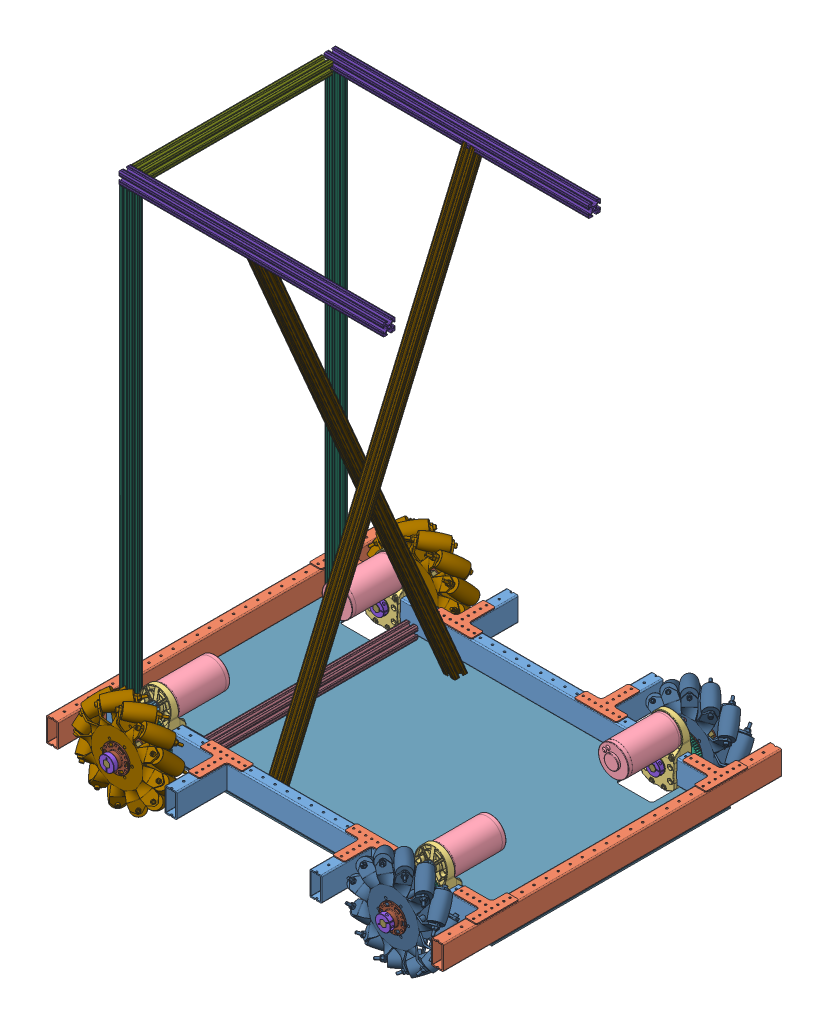
SolidWorks assembly 2018-202-Chassis, configuration Default. Lengths in mm.
Overall size (847.68 1105.96 717.55).
78 component instances, 20 part files, 152 mates.
Components (placement in the parent):
- 2018-200-D002-1: 2018-200-D002 [Default] at (0 101.6 241.3) x (0 0 -1) z (1 0 0) size (25.4 50.8 784.22)
- 2018-200-D002-2: 2018-200-D002 [Default] at (0 101.6 -241.3) x (0 0 -1) z (1 0 0) size (25.4 50.8 784.22)
- 2018-200-D001-2: 2018-200-D001 [Default] at (-404.8125 101.6 0) size (25.4 50.8 711.2)
- 2018-201A-1: 2018-201A [Default] at (-290.5125 96.52 234.85) x (-1 0 0) z (0 0 -1) size (91.39 133.93 154.93)
  - 2018-200-D003-1: 2018-200-D003 [Default] at origin size (69.6 129.7 39.75)
  - 2018-201-D001-1: 2018-201-D001 [Default] at (35.56 -50.8 10.8) x (-1 0 0) z (0 0 -1) size (64.01 64.01 154.93)
  - 2018-201-D002-1: 2018-201-D002 [Default] at (0 58.4962 -28.318) x (0 1 0) z (0 0 1) size (20.01 20.32 19.05)
  - 2018-201-D003-1: 2018-201-D003 [Default] at (0 5.08 -33.0805) size (91.39 91.44 12.65)
  - 2018-201-D007-1: 2018-201-D007 [Default] at (0 5.08 6.35) x (0.5 0.866025 0) z (0.866025 -0.5 0) size (31.12 7.94 31.12)
  - 2018-201-D007-2: 2018-201-D007 [Default] at (0 5.08 -19.05) x (-0.5 -0.866025 0) z (0.866025 -0.5 0) size (31.12 7.94 31.12)
  - 2018-200-D006-1: 2018-200-D006 [Default] at (0.0058 5.07 23.8125) x (1 0 0) z (0 1 0) size (31.47 9.53 31.5)
- 2018-201A-2: 2018-201A [Default] at (290.5125 96.52 234.85) x (-1 0 0) z (0 0 -1) size (91.39 133.93 154.93)
  - 2018-200-D003-1: 2018-200-D003 [Default] at origin size (69.6 129.7 39.75)
  - 2018-201-D001-1: 2018-201-D001 [Default] at (35.56 -50.8 10.8) x (-1 0 0) z (0 0 -1) size (64.01 64.01 154.93)
  - 2018-201-D002-1: 2018-201-D002 [Default] at (0 58.4962 -28.318) x (0 1 0) z (0 0 1) size (20.01 20.32 19.05)
  - 2018-201-D003-1: 2018-201-D003 [Default] at (0 5.08 -33.0805) size (91.39 91.44 12.65)
  - 2018-201-D007-1: 2018-201-D007 [Default] at (0 5.08 6.35) x (0.5 0.866025 0) z (0.866025 -0.5 0) size (31.12 7.94 31.12)
  - 2018-201-D007-2: 2018-201-D007 [Default] at (0 5.08 -19.05) x (-0.5 -0.866025 0) z (0.866025 -0.5 0) size (31.12 7.94 31.12)
  - 2018-200-D006-1: 2018-200-D006 [Default] at (0.0058 5.07 23.8125) x (1 0 0) z (0 1 0) size (31.47 9.53 31.5)
- 2018-201A-3: 2018-201A [Default] at (-290.5125 96.52 -235.05) size (91.39 133.93 154.93)
  - 2018-200-D003-1: 2018-200-D003 [Default] at origin size (69.6 129.7 39.75)
  - 2018-201-D001-1: 2018-201-D001 [Default] at (35.56 -50.8 10.8) x (-1 0 0) z (0 0 -1) size (64.01 64.01 154.93)
  - 2018-201-D002-1: 2018-201-D002 [Default] at (0 58.4962 -28.318) x (0 1 0) z (0 0 1) size (20.01 20.32 19.05)
  - 2018-201-D003-1: 2018-201-D003 [Default] at (0 5.08 -33.0805) size (91.39 91.44 12.65)
  - 2018-201-D007-1: 2018-201-D007 [Default] at (0 5.08 6.35) x (0.5 0.866025 0) z (0.866025 -0.5 0) size (31.12 7.94 31.12)
  - 2018-201-D007-2: 2018-201-D007 [Default] at (0 5.08 -19.05) x (-0.5 -0.866025 0) z (0.866025 -0.5 0) size (31.12 7.94 31.12)
  - 2018-200-D006-1: 2018-200-D006 [Default] at (0.0058 5.07 23.8125) x (1 0 0) z (0 1 0) size (31.47 9.53 31.5)
- 2018-201A-4: 2018-201A [Default] at (290.5125 96.52 -235.05) size (91.39 133.93 154.93)
  - 2018-200-D003-1: 2018-200-D003 [Default] at origin size (69.6 129.7 39.75)
  - 2018-201-D001-1: 2018-201-D001 [Default] at (35.56 -50.8 10.8) x (-1 0 0) z (0 0 -1) size (64.01 64.01 154.93)
  - 2018-201-D002-1: 2018-201-D002 [Default] at (0 58.4962 -28.318) x (0 1 0) z (0 0 1) size (20.01 20.32 19.05)
  - 2018-201-D003-1: 2018-201-D003 [Default] at (0 5.08 -33.0805) size (91.39 91.44 12.65)
  - 2018-201-D007-1: 2018-201-D007 [Default] at (0 5.08 6.35) x (0.5 0.866025 0) z (0.866025 -0.5 0) size (31.12 7.94 31.12)
  - 2018-201-D007-2: 2018-201-D007 [Default] at (0 5.08 -19.05) x (-0.5 -0.866025 0) z (0.866025 -0.5 0) size (31.12 7.94 31.12)
  - 2018-200-D006-1: 2018-200-D006 [Default] at (0.0058 5.07 23.8125) x (1 0 0) z (0 1 0) size (31.47 9.53 31.5)
- 2018-200-D001-3: 2018-200-D001 [Default] at (404.8125 101.6 0) size (25.4 50.8 711.2)
- 2018-200-D004-Left-1: 2018-200-D004-Left [Default] at (-277.7318 118.2849 307.4097) x (-1 0 0) z (0 0 1) size (208.7 208.7 65.41)
- 2018-200-D004-Left-2: 2018-200-D004-Left [Default] at (-269.698 104.3993 -307.6097) x (-0.5 -0.866025 0) z (0 0 -1) size (208.7 208.7 65.41)
- 2018-200-D004-Right-1: 2018-200-D004-Right [Default] at (259.1745 95.1764 -310.8452) size (213.35 213.35 65.46)
- 2018-200-D004-Right-2: 2018-200-D004-Right [Default] at (319.1455 87.387 310.6452) x (-0.965926 0.258819 0) z (0 0 -1) size (213.35 213.35 65.46)
- 2018-200-D005-1: 2018-200-D005 [Default] at (-290.5379 101.6733 -346.8451) x (0 0 1) z (-0.5 -0.866025 0) size (12.7 55.88 55.88)
- 2018-200-D005-2: 2018-200-D005 [Default] at (-290.5379 101.6733 -274.4551) x (0 0 -1) z (0.5 0.866025 0) size (12.7 55.88 55.88)
- 2018-200-D005-3: 2018-200-D005 [Default] at (-290.5125 101.6 346.6451) x (0 0 -1) z (-0.5 -0.866025 0) size (12.7 55.88 55.88)
- 2018-200-D005-5: 2018-200-D005 [Default] at (-290.5125 101.6 274.2551) x (0 0 1) z (1 0 0) size (12.7 55.88 55.88)
- 2018-200-D006-1: 2018-200-D006 [Default] at (-290.5252 101.6073 356.1701) x (0 -1 0) z (1 0 0) size (31.47 9.53 31.5)
- 2018-200-D006-2: 2018-200-D006 [Default] at (290.5506 101.6953 356.1701) x (0.866025 0.5 0) z (-0.5 0.866025 0) size (31.47 9.53 31.5)
- 2018-200-D006-3: 2018-200-D006 [Default] at (-290.5252 101.6513 -346.8451) x (0 1 0) z (-1 0 0) size (31.47 9.53 31.5)
- 2018-200-D006-4: 2018-200-D006 [Default] at (290.5087 101.5858 -346.8451) x (-0.707107 0.707107 0) z (-0.707107 -0.707107 0) size (31.47 9.53 31.5)
- 2018-200-D005-6: 2018-200-D005 [Default] at (290.5379 101.7027 346.6451) x (0 0 -1) z (1 0 0) size (12.7 55.88 55.88)
- 2018-200-D005-7: 2018-200-D005 [Default] at (290.5125 101.6 -274.4551) x (0 0 -1) z (0.707107 0.707107 0) size (12.7 55.88 55.88)
- 2018-200-D005-9: 2018-200-D005 [Default] at (290.5125 101.6 -346.8451) x (0 0 1) z (-0.965926 0.258819 0) size (12.7 55.88 55.88)
- 2018-200-D005-10: 2018-200-D005 [Default] at (290.5379 101.7027 274.2551) x (0 0 1) z (0.5 -0.866025 0) size (12.7 55.88 55.88)
- 2018-200-D007-1: 2018-200-D007 [Default] at (290.5633 101.688 438.7201) x (0 -1 0) z (0 0 1) size (14.48 12.67 146.05)
- 2018-200-D007-2: 2018-200-D007 [Default] at (-290.5252 101.5927 438.7201) x (-0.866025 0.5 0) z (0 0 1) size (14.48 12.67 146.05)
- 2018-200-D007-3: 2018-200-D007 [Default] at (-290.5125 101.6587 -127.7701) x (-0.866025 -0.5 0) z (0 0 1) size (14.48 12.67 146.05)
- 2018-200-D007-4: 2018-200-D007 [Default] at (290.5229 101.5896 -127.7701) x (-0.258819 -0.965926 0) z (0 0 1) size (14.48 12.67 146.05)
- 2018-200-D009-1: 2018-200-D009 [Default] at (-227.0125 88.9 228.6) size (25.4 25.4 450.85)
- 2018-200-D008-1: 2018-200-D008 [Default] at (0 74.6125 3.175) size (835.02 3.17 501.65)
- 2018-200-D010-1: 2018-200-D010 [Default] at (-379.4125 590.55 215.9) x (1 0 0) z (0 -1 0) size (25.4 25.4 965.2)
- 2018-200-D010-2: 2018-200-D010 [Default] at (-379.4125 527.05 -215.9) x (1 0 0) z (0 1 0) size (25.4 25.4 965.2)
- 2018-200-D011-1: 2018-200-D011 [Default] at (-379.4125 1054.1 254) size (25.4 25.4 400.05)
- 2018-200-D012-1: 2018-200-D012 [Default] at (-287.3375 1054.1 215.9) x (0 0 1) z (-1 0 0) size (25.4 25.4 555.62) (hidden)
- 2018-200-D012-2: 2018-200-D012 [Default] at (-287.3375 1054.1 -215.9) x (0 0 1) z (-1 0 0) size (25.4 25.4 555.62)
- 2018-200-D013-1: 2018-200-D013 [Default] at (-114.3 965.3313 180.0515) x (1 0 0) z (0 0.91886 0.394583) size (25.4 25.4 1069)
- 2018-200-D012-3: 2018-200-D012 [Default] at (-287.3375 1054.1 215.9) x (0 0 1) z (-1 0 0) size (25.4 25.4 555.62)
- 2018-200-D013-2: 2018-200-D013 [Default] at (-88.9 965.3313 -180.0515) x (-1 0 0) z (0 0.91886 -0.394583) size (25.4 25.4 1069)
- 2018-200-D014-1: 2018-200-D014 [Default] at (-152.4 101.6 306.3875) size (25.4 50.8 104.77)
- 2018-200-D014-2: 2018-200-D014 [Default] at (152.4 101.6 306.3875) size (25.4 50.8 104.77)
- 2018-200-D014-3: 2018-200-D014 [Default] at (152.4 101.6 -306.3875) size (25.4 50.8 104.77)
- 2018-200-D014-4: 2018-200-D014 [Default] at (-152.4 101.6 -306.3875) size (25.4 50.8 104.77)
- 2018-200-D015-1: 2018-200-D015 [Default] at (-152.4 129.286 -254) x (1 0 0) z (0 -1 0) size (88.9 82.55 2.29)
- 2018-200-D015-2: 2018-200-D015 [Default] at (392.1125 127 241.3) x (0 0 1) z (0 1 0) size (88.9 82.55 2.29)
- 2018-200-D015-3: 2018-200-D015 [Default] at (392.1125 129.286 -241.3) x (0 0 -1) z (0 -1 0) size (88.9 82.55 2.29)
- 2018-200-D015-4: 2018-200-D015 [Default] at (152.4 129.286 -254) x (1 0 0) z (0 -1 0) size (88.9 82.55 2.29)
- 2018-200-D015-5: 2018-200-D015 [Default] at (-392.1125 129.286 241.3) x (0 0 1) z (0 -1 0) size (88.9 82.55 2.29) (hidden)
- 2018-200-D015-6: 2018-200-D015 [Default] at (152.4 127 254) x (1 0 0) z (0 1 0) size (88.9 82.55 2.29)
- 2018-200-D015-7: 2018-200-D015 [Default] at (-392.1125 129.286 -241.3) x (0 0 1) z (0 -1 0) size (88.9 82.55 2.29)
- 2018-200-D015-8: 2018-200-D015 [Default] at (-152.4 127 254) x (1 0 0) z (0 1 0) size (88.9 82.55 2.29)
Mates (geometry in assembly coordinates):
- Coincident5: coincident aligned: plane of 2018-200-D002-1 through (-392.1125 127 254) normal (0 1 0); plane of 2018-200-D001-2 through (-417.5125 127 -355.6) normal (0 1 0)
- Coincident9: coincident aligned: plane of 2018-200-D002-2 through (0 101.6 -228.6) normal (1 0 0); plane of assembly through (0 0 0) normal (1 0 0)
- Coincident23: coincident anti-aligned: plane of 2018-200-D002-2 through (0 101.6 -241.3) normal (0 0 -1); plane of 2018-201A-4/2018-200-D003-1 through (255.6275 71.12 -241.3) normal (0 0 1)
- Parallel3: parallel anti-aligned: plane of 2018-200-D002-2 through (392.1125 76.2 -215.9) normal (0 -1 0); plane of 2018-201A-4/2018-200-D003-1 through (256.7625 71.12 -216.1) normal (0 1 0)
- Coincident24: coincident anti-aligned: plane of 2018-200-D002-2 through (0 101.6 -241.3) normal (0 0 -1); plane of 2018-201A-3/2018-200-D003-1 through (-325.3975 71.12 -241.3) normal (0 0 1)
- Parallel4: parallel anti-aligned: plane of 2018-200-D002-2 through (392.1125 76.2 -215.9) normal (0 -1 0); plane of 2018-201A-3/2018-200-D003-1 through (-325.3975 71.12 -222.35) normal (0 1 0)
- Coincident26: coincident anti-aligned: plane of 2018-200-D002-1 through (0 101.6 228.6) normal (0 0 -1); plane of 2018-201A-2/2018-200-D003-1 through (324.2625 71.12 228.6) normal (0 0 1)
- Parallel5: parallel anti-aligned: plane of 2018-200-D002-1 through (392.1125 76.2 254) normal (0 -1 0); plane of 2018-201A-2/2018-200-D003-1 through (325.3975 71.12 234.85) normal (0 1 0)
- Concentric24: concentric aligned: cylinder of 2018-200-D002-1 through (-290.5125 101.6 254) axis (0 0 -1) radius 14.3002; cylinder of 2018-201A-1/2018-200-D003-1 through (-290.5125 101.6 237.85) axis (0 0 -1) radius 14.3002
- Coincident27: coincident anti-aligned: plane of 2018-200-D002-1 through (0 101.6 228.6) normal (0 0 -1); plane of 2018-201A-1/2018-200-D003-1 through (-256.7625 71.12 228.6) normal (0 0 1)
- Parallel6: parallel anti-aligned: plane of 2018-200-D002-1 through (392.1125 76.2 254) normal (0 -1 0); plane of 2018-201A-1/2018-200-D003-1 through (-255.6275 71.12 234.85) normal (0 1 0)
- Concentric25: concentric anti-aligned: cylinder of 2018-200-D002-2 through (-290.5125 101.6 -215.9) axis (0 0 -1) radius 14.3002; cylinder of 2018-201A-3/2018-200-D003-1 through (-290.5125 101.6 -225.35) axis (0 0 1) radius 14.3002
- Coincident31: coincident aligned: plane of 2018-200-D001-2 through (-404.8125 101.6 0) normal (0 0 1); plane of assembly through (0 0 0) normal (0 0 1)
- Coincident32: coincident aligned: plane of 2018-200-D002-1 through (-392.1125 127 254) normal (0 1 0); plane of 2018-200-D002-2 through (-392.1125 127 -215.9) normal (0 1 0)
- Coincident34: coincident anti-aligned: plane of 2018-200-D002-1 through (-392.1125 76.2 254) normal (-1 0 0); plane of 2018-200-D001-2 through (-392.1125 101.6 0) normal (1 0 0)
- Coincident35: coincident anti-aligned: plane of 2018-200-D002-2 through (-392.1125 76.2 -215.9) normal (-1 0 0); plane of 2018-200-D001-2 through (-392.1125 101.6 0) normal (1 0 0)
- Distance5: distance = 101.6 mm aligned: plane of 2018-200-D002-1 through (0 101.6 254) normal (0 0 1); plane of 2018-200-D001-2 through (-417.5125 127 355.6) normal (0 0 1)
- Distance6: distance = 101.6 mm aligned: plane of 2018-200-D002-1; plane of assembly through (0 0 0) normal (0 1 0)
- Distance9: distance = 101.6 mm aligned: plane of 2018-200-D002-2 through (0 101.6 -254) normal (0 0 -1); plane of 2018-200-D001-2 through (-417.5125 76.2 -355.6) normal (0 0 -1)
- Coincident40: coincident anti-aligned: plane of 2018-200-D002-1 through (392.1125 127 254) normal (1 0 0); plane of 2018-200-D001-3 through (392.1125 101.6 0) normal (-1 0 0)
- Coincident41: coincident aligned: plane of 2018-200-D001-2 through (-417.5125 127 -355.6) normal (0 1 0); plane of 2018-200-D001-3 through (392.1125 127 -355.6) normal (0 1 0)
- Coincident42: coincident aligned: plane of 2018-200-D001-2 through (-417.5125 127 355.6) normal (0 0 1); plane of 2018-200-D001-3 through (392.1125 127 355.6) normal (0 0 1)
- Concentric27: concentric anti-aligned: cylinder of 2018-200-D002-1 through (-290.5125 101.6 254) axis (0 0 -1) radius 14.3002; cylinder of 2018-200-D004-Left-1 through (-290.5125 101.6 342.4604) axis (0 0 1) radius 14.2875
- Concentric28: concentric aligned: cylinder of 2018-200-D002-2 through (290.5125 101.6 -215.9) axis (0 0 -1) radius 14.3002; cylinder of 2018-200-D004-Right-1 through (290.5125 101.6 -274.4551) axis (0 0 -1) radius 14.2875
- Coincident47: coincident anti-aligned: plane of 2018-200-D004-Left-1 through (-343.8525 48.26 333.9451) normal (0 0 1); plane of 2018-200-D005-3 through (-263.1922 85.8266 333.9451) normal (0 0 -1)
- Concentric34: concentric aligned: cylinder of 2018-200-D004-Left-1 through (-290.5125 101.6 342.4604) axis (0 0 1) radius 14.2875; cylinder of 2018-200-D005-3 through (-290.5125 101.6 332.3449) axis (0 0 1) radius 27.94
- Concentric35: concentric aligned: cylinder of 2018-200-D004-Left-1 through (-290.5125 77.7875 320.6797) axis (0 0 -1) radius 2.667; cylinder of 2018-200-D005-3 through (-290.5125 77.7875 419.7384) axis (0 0 -1) radius 2.15
- Coincident48: coincident anti-aligned: plane of 2018-200-D004-Left-1 through (-237.1725 48.26 286.9551) normal (0 0 -1); plane of 2018-200-D005-5 through (-290.5125 70.0532 286.9551) normal (0 0 1)
- Concentric36: concentric aligned: cylinder of 2018-200-D004-Left-1 through (-290.5125 101.6 278.4397) axis (0 0 -1) radius 14.2875; cylinder of 2018-200-D005-5 through (-290.5125 101.6 288.5553) axis (0 0 -1) radius 27.94
- Concentric37: concentric aligned: cylinder of 2018-200-D004-Left-1 through (-290.5125 77.7875 300.2204) axis (0 0 1) radius 2.667; cylinder of 2018-200-D005-5 through (-290.5125 77.7875 201.1617) axis (0 0 1) radius 2.15
- Coincident49: coincident anti-aligned: plane of 2018-200-D005-3 through (-290.5125 101.6 346.6451) normal (0 0 1); plane of 2018-200-D006-1 through (-290.5252 101.6073 346.6451) normal (0 0 -1)
- Coincident50: coincident aligned: plane of 2018-200-D005-3 through (-296.8752 97.9265 346.6451) normal (1 0 0); plane of 2018-200-D006-1 through (-296.8752 97.9412 346.6451) normal (1 0 0)
- Coincident51: coincident aligned: plane of 2018-200-D005-3 through (-296.8752 105.2735 346.6451) normal (0.5 -0.866025 0); plane of 2018-200-D006-1 through (-296.8752 105.2735 346.6451) normal (0.5 -0.866025 0)
- Coincident52: coincident anti-aligned: plane of 2018-201A-1/2018-201-D003-1 through (-290.5125 101.6 274.2551) normal (0 0 1); plane of 2018-200-D005-5 through (-290.5125 101.6 274.2551) normal (0 0 -1)
- Coincident59: coincident anti-aligned: plane of 2018-200-D004-Right-1 through (310.0296 28.7612 -274.4551) normal (0 0 1); plane of 2018-200-D005-7 through (268.2055 123.907 -274.4551) normal (0 0 -1)
- Concentric42: concentric anti-aligned: cylinder of 2018-200-D004-Right-1 through (290.5125 101.6 -274.4551) axis (0 0 -1) radius 14.2875; cylinder of 2018-200-D005-7 through (290.5125 101.6 -276.0553) axis (0 0 1) radius 27.94
- Concentric43: concentric aligned: cylinder of 2018-200-D004-Right-1 through (296.6756 124.6011 -274.4551) axis (0 0 -1) radius 2.6035; cylinder of 2018-200-D005-7 through (296.6756 124.6011 -188.6617) axis (0 0 -1) radius 2.15
- Coincident60: coincident anti-aligned: plane of 2018-200-D004-Right-1 through (310.0296 28.7612 -321.4451) normal (0 0 -1); plane of 2018-200-D005-9 through (298.6774 132.0719 -321.4451) normal (0 0 1)
- Concentric44: concentric anti-aligned: cylinder of 2018-200-D004-Right-1 through (290.5125 101.6 -321.4451) axis (0 0 1) radius 14.2875; cylinder of 2018-200-D005-9 through (290.5125 101.6 -319.8449) axis (0 0 -1) radius 27.94
- Concentric45: concentric aligned: cylinder of 2018-200-D004-Right-1 through (296.6756 124.6011 -321.4451) axis (0 0 1) radius 2.6035; cylinder of 2018-200-D005-9 through (296.6756 124.6011 -407.2384) axis (0 0 1) radius 2.15
- Coincident64: coincident aligned: plane of 2018-200-D006-4 through (288.611 94.5033 -343.6701) normal (0.707107 0.707107 0); plane of 2018-200-D005-9 through (283.4158 99.6985 -334.1451) normal (0.707107 0.707107 0)
- Coincident65: coincident anti-aligned: plane of 2018-200-D006-4 through (290.5087 101.5858 -334.1451) normal (0 0 1); plane of 2018-200-D005-9 through (290.5125 101.6 -334.1451) normal (0 0 -1)
- Coincident66: coincident aligned: plane of 2018-200-D006-4 through (295.6935 96.4011 -343.6701) normal (-0.258819 0.965926 0); plane of 2018-200-D005-9 through (288.611 94.5033 -334.1451) normal (-0.258819 0.965926 0)
- Concentric48: concentric aligned: cylinder of 2018-200-D002-1 through (290.5125 101.6 254) axis (0 0 -1) radius 14.3002; cylinder of 2018-201A-2/2018-200-D003-1 through (290.5125 101.6 237.85) axis (0 0 -1) radius 14.3002
- Concentric49: concentric anti-aligned: cylinder of 2018-200-D002-2 through (290.5125 101.6 -215.9) axis (0 0 -1) radius 14.3002; cylinder of 2018-201A-4/2018-200-D003-1 through (290.5125 101.6 -225.35) axis (0 0 1) radius 14.3002
- Coincident78: coincident aligned: plane of 2018-200-D006-1 through (-290.5252 101.6073 356.1701) normal (0 0 1); plane of 2018-200-D007-2 through (-284.6959 104.9582 356.1701) normal (0 0 1)
- Coincident79: coincident anti-aligned: plane of 2018-200-D006-1 through (-290.5252 94.275 346.6451) normal (0.5 0.866025 0); plane of 2018-200-D007-2 through (-290.7792 94.4216 356.1701) normal (-0.5 -0.866025 0)
- Coincident81: coincident anti-aligned: plane of 2018-200-D006-1 through (-284.1752 97.9412 346.6451) normal (-0.5 0.866025 0); plane of 2018-200-D007-2 through (-284.4419 97.7872 356.1701) normal (0.5 -0.866025 0)
- Coincident82: coincident aligned: plane of 2018-200-D006-4 through (290.5087 101.5858 -343.6701) normal (0 0 -1); plane of 2018-200-D007-4 through (285.7633 106.3492 -343.6701) normal (0 0 -1)
- Coincident83: coincident anti-aligned: plane of 2018-200-D006-4 through (297.5912 103.4836 -343.6701) normal (-0.965926 0.258819 0); plane of 2018-200-D007-4 through (297.5153 103.2003 -197.6201) normal (0.965926 -0.258819 0)
- Coincident84: coincident anti-aligned: plane of 2018-200-D006-4 through (292.4065 108.6683 -343.6701) normal (-0.707107 -0.707107 0); plane of 2018-200-D007-4 through (292.6242 108.4506 -197.6201) normal (0.707107 0.707107 0)
- Coincident87: coincident anti-aligned: plane of 2018-200-D006-3 through (-290.5252 108.9837 -343.6701) normal (-0.5 -0.866025 0); plane of 2018-200-D007-3 through (-290.2585 108.8297 -197.6201) normal (0.5 0.866025 0)
- Coincident88: coincident anti-aligned: plane of 2018-200-D006-3 through (-284.1752 105.3175 -343.6701) normal (-1 0 0); plane of 2018-200-D007-3 through (-284.1752 105.0242 -197.6201) normal (1 0 0)
- Parallel11: parallel anti-aligned: plane of 2018-200-D004-Left-1; plane of assembly through (0 0 0) normal (0 1 0)
- Parallel14: parallel aligned: plane of 2018-200-D004-Right-1 through (259.1745 95.1764 -298.1452) normal (0 1 0); plane of assembly through (0 0 0) normal (0 1 0)
- Coincident91: coincident anti-aligned: plane of 2018-200-D002-1 through (0 101.6 228.6) normal (0 0 -1); plane of 2018-200-D009-1 through (-237.6043 78.3082 228.6) normal (0 0 1)
- Distance10: distance = 152.4 mm anti-aligned: plane of 2018-200-D009-1 through (-239.7125 95.2331 228.6) normal (-1 0 0); plane of 2018-200-D001-2 through (-392.1125 101.6 0) normal (1 0 0)
- Coincident100: coincident anti-aligned: plane of 2018-200-D001-2 through (-392.1125 101.6 0) normal (1 0 0); plane of 2018-200-D010-1 through (-392.1125 76.2 222.2331) normal (-1 0 0)
- Coincident101: coincident anti-aligned: plane of 2018-200-D002-1 through (0 101.6 228.6) normal (0 0 -1); plane of 2018-200-D010-1 through (-373.0794 76.2 228.6) normal (0 0 1)
- Coincident103: coincident anti-aligned: plane of 2018-200-D001-2 through (-392.1125 101.6 0) normal (1 0 0); plane of 2018-200-D010-2 through (-392.1125 1041.4 -209.5331) normal (-1 0 0)
- Coincident104: coincident anti-aligned: plane of 2018-200-D002-2 through (0 101.6 -215.9) normal (0 0 1); plane of 2018-200-D010-2 through (-388.9629 1041.4 -215.9) normal (0 0 -1)
- Coincident105: coincident anti-aligned: plane of 2018-200-D010-1 through (-369.8621 76.2 203.2) normal (0 0 -1); plane of 2018-200-D011-1 through (-390.0043 1043.5082 203.2) normal (0 0 1)
- Coincident107: coincident aligned: plane of 2018-200-D010-2 through (-366.7125 1041.4 -196.8669) normal (1 0 0); plane of 2018-200-D011-1 through (-366.7125 1063.6504 203.2) normal (1 0 0)
- Coincident108: coincident anti-aligned: plane of 2018-200-D001-2 through (-417.5125 76.2 355.6) normal (0 -1 0); plane of 2018-200-D008-1 through (0 76.2 3.175) normal (0 1 0)
- Coincident109: coincident aligned: plane of 2018-200-D001-2 through (-417.5125 101.6 0) normal (-1 0 0); plane of 2018-200-D008-1 through (-417.5125 76.2 254) normal (-1 0 0)
- Coincident110: coincident aligned: plane of 2018-200-D002-1 through (0 101.6 254) normal (0 0 1); plane of 2018-200-D008-1 through (417.5125 76.2 254) normal (0 0 1)
- Coincident111: coincident anti-aligned: plane of 2018-200-D009-1 through (-217.4621 76.2 228.6) normal (0 -1 0); plane of 2018-200-D008-1 through (0 76.2 3.175) normal (0 1 0)
- Coincident113: coincident aligned: plane of 2018-200-D010-1 through (-392.1125 76.2 222.2331) normal (-1 0 0); plane of 2018-200-D012-1 through (-392.1125 1043.5082 205.3082) normal (-1 0 0)
- Coincident114: coincident aligned: plane of 2018-200-D010-1 through (-373.0794 76.2 228.6) normal (0 0 1); plane of 2018-200-D012-1 through (-392.1125 1063.6504 228.6) normal (0 0 1)
- Coincident115: coincident anti-aligned: plane of 2018-200-D010-1 through (-390.0043 1041.4 205.3082) normal (0 1 0); plane of 2018-200-D012-1 through (-392.1125 1041.4 225.4504) normal (0 -1 0)
- Coincident116: coincident aligned: plane of 2018-200-D012-1 through (-392.1125 1043.5082 205.3082) normal (-1 0 0); plane of 2018-200-D012-2 through (-392.1125 1043.5082 -213.7918) normal (-1 0 0)
- Coincident117: coincident aligned: plane of 2018-200-D010-2 through (-388.9629 1041.4 -215.9) normal (0 0 -1); plane of 2018-200-D012-2 through (-392.1125 1044.5496 -215.9) normal (0 0 -1)
- Coincident118: coincident anti-aligned: plane of 2018-200-D010-2 through (-390.0043 1041.4 -192.6082) normal (0 1 0); plane of 2018-200-D012-2 through (-392.1125 1041.4 -193.6496) normal (0 -1 0)
- Coincident119: coincident aligned: plane of 2018-200-D011-1 through (-373.0794 1066.8 203.2) normal (0 1 0); plane of 2018-200-D012-1 through (-392.1125 1066.8 206.3496) normal (0 1 0)
- Coincident120: coincident aligned: plane of 2018-200-D011-1 through (-373.0794 1066.8 203.2) normal (0 1 0); plane of 2018-200-D012-2 through (-392.1125 1066.8 -196.8669) normal (0 1 0)
- Coincident121: coincident anti-aligned: plane of 2018-200-D008-1 through (0 76.2 3.175) normal (0 1 0); plane of 2018-200-D010-1 through (-390.0043 76.2 205.3082) normal (0 -1 0)
- Coincident132: coincident anti-aligned: plane of 2018-200-D010-1 through (-390.0043 1041.4 205.3082) normal (0 1 0); plane of 2018-200-D012-3 through (-392.1125 1041.4 225.4504) normal (0 -1 0)
- Coincident133: coincident anti-aligned: plane of 2018-200-D011-1 through (-390.0043 1043.5082 203.2) normal (0 0 1); plane of 2018-200-D012-3 through (-392.1125 1060.4331 203.2) normal (0 0 -1)
- Coincident134: coincident aligned: plane of 2018-200-D011-1 through (-392.1125 1060.4331 203.2) normal (-1 0 0); plane of 2018-200-D012-3 through (-392.1125 1043.5082 205.3082) normal (-1 0 0)
- Coincident139: coincident anti-aligned: plane of 2018-200-D013-1 through (-101.6 1043.9122 220.6886) normal (1 0 0); plane of 2018-200-D013-2 through (-101.6 1050.1796 -193.3939) normal (-1 0 0)
- Distance11: distance = 265.1125 mm anti-aligned: plane of 2018-200-D013-2 through (-101.6 1050.1796 -206.0939) normal (-1 0 0); plane of 2018-200-D012-2 through (163.5125 1043.5082 -226.4918) normal (1 0 0)
- Coincident140: coincident anti-aligned: plane of 2018-200-D002-1 through (0 101.6 254) normal (0 0 1); plane of 2018-200-D014-2 through (139.7 76.2 254) normal (0 0 -1)
- Coincident141: coincident aligned: plane of 2018-200-D002-1 through (-392.1125 127 254) normal (0 1 0); plane of 2018-200-D014-2 through (139.7 127 254) normal (0 1 0)
- Coincident142: coincident anti-aligned: plane of 2018-200-D002-1 through (0 101.6 254) normal (0 0 1); plane of 2018-200-D014-1 through (-165.1 76.2 254) normal (0 0 -1)
- Coincident143: coincident aligned: plane of 2018-200-D014-1 through (-165.1 127 254) normal (0 1 0); plane of 2018-200-D014-2 through (139.7 127 254) normal (0 1 0)
- Distance12: distance = 265.1125 mm anti-aligned: plane of 2018-200-D014-1 through (-152.4 101.6 306.3875) normal (1 0 0); plane of 2018-200-D001-2 through (-417.5125 101.6 0) normal (-1 0 0)
- Distance13: distance = 265.1125 mm aligned: plane of 2018-200-D014-2 through (152.4 101.6 306.3875) normal (1 0 0); plane of 2018-200-D001-3 through (417.5125 101.6 0) normal (1 0 0)
- Coincident144: coincident aligned: plane of 2018-200-D014-2 through (139.7 127 254) normal (0 1 0); plane of 2018-200-D014-3 through (139.7 127 -346.075) normal (0 1 0)
- Coincident145: coincident aligned: plane of 2018-200-D014-2 through (165.1 101.6 306.3875) normal (1 0 0); plane of 2018-200-D014-3 through (165.1 101.6 -293.6875) normal (1 0 0)
- Coincident146: coincident anti-aligned: plane of 2018-200-D002-2 through (0 101.6 -241.3) normal (0 0 -1); plane of 2018-200-D014-3 through (139.7 127 -241.3) normal (0 0 1)
- Coincident147: coincident aligned: plane of 2018-200-D014-3 through (139.7 127 -346.075) normal (0 1 0); plane of 2018-200-D014-4 through (-165.1 127 -346.075) normal (0 1 0)
- Coincident148: coincident aligned: plane of 2018-200-D014-1 through (-139.7 101.6 306.3875) normal (1 0 0); plane of 2018-200-D014-4 through (-139.7 101.6 -293.6875) normal (1 0 0)
- Coincident149: coincident anti-aligned: plane of 2018-200-D002-2 through (0 101.6 -241.3) normal (0 0 -1); plane of 2018-200-D014-4 through (-165.1 127 -241.3) normal (0 0 1)
- Coincident150: coincident anti-aligned: plane of 2018-200-D001-3 through (392.1125 127 -355.6) normal (0 1 0); plane of 2018-200-D015-2 through (385.7625 127 260.35) normal (0 -1 0)
- Coincident151: coincident aligned: plane of 2018-200-D001-3 through (417.5125 101.6 0) normal (1 0 0); plane of 2018-200-D015-2 through (417.5125 127 283.591) normal (1 0 0)
- Coincident154: coincident anti-aligned: plane of 2018-200-D002-1 through (0 101.6 241.3) normal (0 0 -1); plane of 2018-200-D015-2
- Coincident155: coincident anti-aligned: plane of 2018-200-D001-3 through (392.1125 127 -355.6) normal (0 1 0); plane of 2018-200-D015-3 through (385.7625 127 -247.65) normal (0 -1 0)
- Coincident156: coincident aligned: plane of 2018-200-D001-3 through (417.5125 101.6 0) normal (1 0 0); plane of 2018-200-D015-3 through (417.5125 129.286 -270.891) normal (1 0 0)
- Coincident157: coincident aligned: plane of 2018-200-D002-2 through (0 101.6 -228.6) normal (0 0 -1); plane of 2018-200-D015-3
- Coincident158: coincident anti-aligned: plane of 2018-200-D001-2 through (-417.5125 127 -355.6) normal (0 1 0); plane of 2018-200-D015-5 through (-385.7625 127 260.35) normal (0 -1 0)
- Coincident159: coincident aligned: plane of 2018-200-D001-2 through (-417.5125 101.6 0) normal (-1 0 0); plane of 2018-200-D015-5 through (-417.5125 129.286 283.591) normal (-1 0 0)
- Coincident160: coincident aligned: plane of 2018-200-D015-2 through (337.1215 127 254) normal (0 0 1); plane of 2018-200-D015-5 through (-337.1215 129.286 254) normal (0 0 1)
- Coincident161: coincident anti-aligned: plane of 2018-200-D001-2 through (-417.5125 127 -355.6) normal (0 1 0); plane of 2018-200-D015-7 through (-385.7625 127 -209.55) normal (0 -1 0)
- Coincident162: coincident aligned: plane of 2018-200-D001-2 through (-417.5125 101.6 0) normal (-1 0 0); plane of 2018-200-D015-7 through (-417.5125 129.286 -186.309) normal (-1 0 0)
- Coincident163: coincident aligned: plane of 2018-200-D015-3 through (385.7625 129.286 -215.9) normal (0 0 1); plane of 2018-200-D015-7 through (-337.1215 129.286 -215.9) normal (0 0 1)
- Coincident164: coincident anti-aligned: plane of 2018-200-D002-1 through (-392.1125 127 254) normal (0 1 0); plane of 2018-200-D015-8 through (-133.35 127 260.35) normal (0 -1 0)
- Coincident165: coincident aligned: plane of 2018-200-D002-1 through (0 101.6 228.6) normal (0 0 -1); plane of 2018-200-D015-8 through (-110.109 127 228.6) normal (0 0 -1)
- Coincident167: coincident aligned: plane of 2018-200-D014-1 through (-152.4 101.6 306.3875) normal (1 0 0); plane of 2018-200-D015-8
- Coincident168: coincident anti-aligned: plane of 2018-200-D014-2 through (139.7 127 254) normal (0 1 0); plane of 2018-200-D015-6 through (171.45 127 260.35) normal (0 -1 0)
- Coincident169: coincident aligned: plane of 2018-200-D002-1 through (0 101.6 228.6) normal (0 0 -1); plane of 2018-200-D015-6 through (194.691 127 228.6) normal (0 0 -1)
- Coincident170: coincident aligned: plane of 2018-200-D014-2 through (152.4 101.6 306.3875) normal (1 0 0); plane of 2018-200-D015-6
- Coincident171: coincident anti-aligned: plane of 2018-200-D002-2 through (-392.1125 127 -215.9) normal (0 1 0); plane of 2018-200-D015-4 through (171.45 127 -247.65) normal (0 -1 0)
- Coincident172: coincident aligned: plane of 2018-200-D002-2 through (0 101.6 -215.9) normal (0 0 1); plane of 2018-200-D015-4 through (194.691 129.286 -215.9) normal (0 0 1)
- Coincident173: coincident aligned: plane of 2018-200-D015-4 through (165.1 129.286 -296.291) normal (1 0 0); plane of 2018-200-D015-6 through (165.1 127 308.991) normal (1 0 0)
- Coincident174: coincident anti-aligned: plane of 2018-200-D002-2 through (-392.1125 127 -215.9) normal (0 1 0); plane of 2018-200-D015-1 through (-133.35 127 -247.65) normal (0 -1 0)
- Coincident175: coincident aligned: plane of 2018-200-D002-2 through (0 101.6 -215.9) normal (0 0 1); plane of 2018-200-D015-1 through (-110.109 129.286 -215.9) normal (0 0 1)
- Coincident176: coincident aligned: plane of 2018-200-D015-1 through (-139.7 129.286 -296.291) normal (1 0 0); plane of 2018-200-D015-8 through (-139.7 127 308.991) normal (1 0 0)
- Coincident183: coincident anti-aligned: plane of 2018-200-D004-Left-2 through (-363.4017 82.1495 -321.4451) normal (0 0 -1); plane of 2018-200-D005-1 through (-317.8582 117.4467 -321.4451) normal (0 0 1)
- Concentric50: concentric anti-aligned: cylinder of 2018-200-D004-Left-2 through (-290.5379 101.6733 -329.9604) axis (0 0 -1) radius 14.2875; cylinder of 2018-200-D005-1 through (-290.5379 101.6733 -321.4451) axis (0 0 1) radius 14.2949
- Concentric51: concentric aligned: cylinder of 2018-200-D004-Left-2 through (-311.1601 113.5796 -308.1797) axis (0 0 1) radius 2.667; cylinder of 2018-200-D005-1 through (-311.1601 113.5796 -407.2384) axis (0 0 1) radius 2.15
- Concentric52: concentric anti-aligned: cylinder of 2018-200-D004-Left-2 through (-311.1601 89.7671 -275.5558) axis (0 0 -1) radius 2.7432; cylinder of 2018-200-D005-1 through (-311.1601 89.7671 -407.2384) axis (0 0 1) radius 2.15
- Coincident184: coincident anti-aligned: plane of 2018-200-D004-Left-2 through (-310.0617 174.5371 -274.4551) normal (0 0 1); plane of 2018-200-D005-2 through (-317.8582 117.4467 -274.4551) normal (0 0 -1)
- Concentric53: concentric anti-aligned: cylinder of 2018-200-D004-Left-2 through (-290.5379 101.6733 -265.9397) axis (0 0 1) radius 14.2875; cylinder of 2018-200-D005-2 through (-290.5379 101.6733 -274.4551) axis (0 0 -1) radius 14.2949
- Concentric54: concentric aligned: cylinder of 2018-200-D004-Left-2 through (-311.1601 113.5796 -287.7204) axis (0 0 -1) radius 2.667; cylinder of 2018-200-D005-2 through (-311.1601 113.5796 -188.6617) axis (0 0 -1) radius 2.15
- Concentric55: concentric aligned: cylinder of 2018-200-D004-Left-2 through (-290.5379 125.4858 -287.7204) axis (0 0 -1) radius 2.667; cylinder of 2018-200-D005-2 through (-290.5379 125.4858 -188.6617) axis (0 0 -1) radius 2.15
- Coincident188: coincident anti-aligned: plane of 2018-201A-2/2018-201-D003-1 through (284.1244 105.2882 274.2551) normal (0.5 -0.866025 0); plane of 2018-200-D007-1 through (284.48 105.4935 356.1701) normal (-0.5 0.866025 0)
- Coincident189: coincident anti-aligned: plane of 2018-201A-2/2018-201-D003-1 through (296.9006 105.2882 274.2551) normal (-1 0 0); plane of 2018-200-D007-1 through (296.9006 105.0535 356.1701) normal (1 0 0)
- Coincident190: coincident anti-aligned: plane of 2018-200-D006-2 through (296.9006 98.0291 346.6451) normal (-0.5 0.866025 0); plane of 2018-200-D007-1 through (296.6466 97.8825 356.1701) normal (0.5 -0.866025 0)
- Coincident192: coincident anti-aligned: plane of 2018-200-D006-2 through (296.9006 105.3615 346.6451) normal (-1 0 0); plane of 2018-200-D007-1 through (296.9006 105.0535 356.1701) normal (1 0 0)
- Coincident196: coincident anti-aligned: plane of 2018-200-D004-Right-2 through (252.8338 36.3972 333.9451) normal (0 0 1); plane of 2018-200-D005-6 through (290.5379 133.2495 333.9451) normal (0 0 -1)
- Concentric56: concentric aligned: cylinder of 2018-200-D004-Right-2 through (290.5379 125.5152 333.9451) axis (0 0 -1) radius 2.6035; cylinder of 2018-200-D005-6 through (290.5379 125.5152 419.7384) axis (0 0 -1) radius 2.15
- Concentric57: concentric aligned: cylinder of 2018-200-D004-Right-2 through (311.1601 89.7964 333.9451) axis (0 0 -1) radius 2.6035; cylinder of 2018-200-D005-6 through (311.1601 89.7964 419.7384) axis (0 0 -1) radius 2.15
- Coincident197: coincident anti-aligned: plane of 2018-200-D004-Right-2 through (252.8338 36.3972 286.9551) normal (0 0 -1); plane of 2018-200-D005-10 through (263.2176 85.9293 286.9551) normal (0 0 1)
- Concentric58: concentric aligned: cylinder of 2018-200-D004-Right-2 through (290.5379 125.5152 330.7701) axis (0 0 1) radius 2.7432; cylinder of 2018-200-D005-10 through (290.5379 125.5152 201.1617) axis (0 0 1) radius 2.15
- Concentric59: concentric aligned: cylinder of 2018-200-D004-Right-2 through (269.9157 113.6089 286.9551) axis (0 0 1) radius 2.6035; cylinder of 2018-200-D005-10 through (269.9157 113.6089 201.1617) axis (0 0 1) radius 2.15
- Coincident202: coincident anti-aligned: plane of 2018-201A-3/2018-201-D003-1 through (-290.5125 108.9763 -261.7551) normal (0.5 -0.866025 0); plane of 2018-200-D007-3 through (-296.5958 105.4641 -197.6201) normal (-0.5 0.866025 0)
- Coincident203: coincident anti-aligned: plane of ? through (-284.1244 105.2882 -261.7551) normal (-0.5 -0.866025 0); plane of 2018-200-D007-3 through (-290.2585 108.8297 -197.6201) normal (0.5 0.866025 0)
- Coincident204: coincident aligned: plane of 2018-200-D006-3 through (-290.5252 101.6513 -343.6701) normal (0 0 -1); plane of 2018-200-D007-3 through (-290.5125 108.3898 -343.6701) normal (0 0 -1)
- Coincident206: coincident aligned: plane of 2018-200-D006-2 through (290.5506 101.6953 356.1701) normal (0 0 1); plane of 2018-200-D007-1 through (284.734 105.0535 356.1701) normal (0 0 1)
- Coincident207: coincident anti-aligned: plane of 2018-200-D013-1 through (-127 1041.4 180.0515) normal (0 1 0); plane of 2018-200-D012-3 through (-392.1125 1041.4 209.5669) normal (0 -1 0)
- Coincident208: coincident anti-aligned: plane of 2018-200-D013-1 through (-127 965.3313 203.2) normal (0 0 1); plane of 2018-200-D012-3 through (-392.1125 1044.5496 203.2) normal (0 0 -1)
- Coincident209: coincident anti-aligned: plane of 2018-200-D012-2 through (-392.1125 1063.6504 -190.5) normal (0 0 1); plane of 2018-200-D013-2 through (-76.2 965.3313 -190.5) normal (0 0 -1)
- Coincident210: coincident anti-aligned: plane of 2018-200-D012-2 through (-392.1125 1041.4 -193.6496) normal (0 -1 0); plane of 2018-200-D013-2 through (-76.2 1041.4 -167.3515) normal (0 1 0)
- Coincident211: coincident anti-aligned: plane of 2018-200-D005-1 through (-290.5379 94.3263 -334.1451) normal (-0.5 0.866025 0); plane of 2018-200-D007-3 through (-284.4292 97.8532 -197.6201) normal (0.5 -0.866025 0)
- Coincident212: coincident anti-aligned: plane of 2018-200-D005-1 through (-284.1752 97.9998 -334.1451) normal (-1 0 0); plane of 2018-200-D007-3 through (-284.1752 105.0242 -197.6201) normal (1 0 0)
- Coincident213: coincident anti-aligned: plane of ? through (-290.5125 101.6 -261.7551) normal (0 0 -1); plane of 2018-200-D005-2 through (-290.5379 101.6733 -261.7551) normal (0 0 1)
- Coincident214: coincident anti-aligned: plane of 2018-200-D005-6 through (296.9006 98.0291 346.6451) normal (-0.5 0.866025 0); plane of 2018-200-D007-1 through (296.6466 97.8825 356.1701) normal (0.5 -0.866025 0)
- Coincident215: coincident anti-aligned: plane of 2018-200-D005-6 through (296.9006 105.3762 346.6451) normal (-1 0 0); plane of 2018-200-D007-1 through (296.9006 105.0535 356.1701) normal (1 0 0)
- Coincident216: coincident anti-aligned: plane of 2018-201A-2/2018-201-D003-1 through (290.5125 101.6 274.2551) normal (0 0 1); plane of 2018-200-D005-10 through (290.5379 101.7027 274.2551) normal (0 0 -1)
- Coincident217: coincident anti-aligned: plane of 2018-200-D006-2 through (290.5506 101.6953 346.6451) normal (0 0 -1); plane of 2018-200-D005-6 through (290.5379 101.7027 346.6451) normal (0 0 1)
- Coincident218: coincident anti-aligned: plane of 2018-200-D005-1 through (-290.5379 101.6733 -334.1451) normal (0 0 -1); plane of 2018-200-D006-3 through (-290.5252 101.6513 -334.1451) normal (0 0 1)
- Coincident219: coincident anti-aligned: plane of 2018-201A-4/2018-201-D003-1 through (290.5125 101.6 -261.7551) normal (0 0 -1); plane of 2018-200-D005-7 through (290.5125 101.6 -261.7551) normal (0 0 1)
